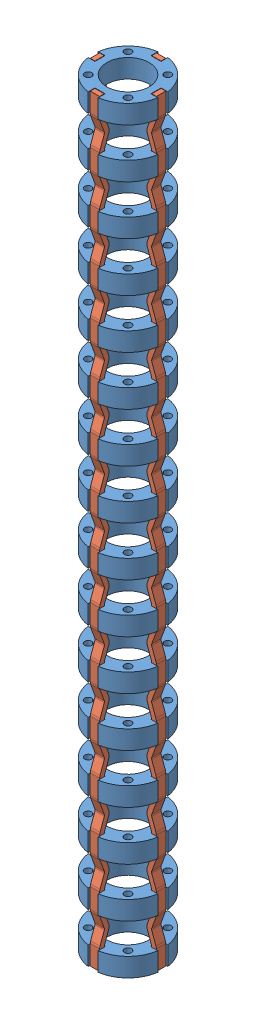
SolidWorks assembly Spine3Segments, configuration Default. Lengths in mm.
Overall size (14.85 161.57 14.85).
20 component instances, 2 part files, 9 mates.
Components (placement in the parent):
- RigidDisc-1: RigidDisc [Default] at (4.4669 6.9477 12.6403) size (14.85 4 14.85)
- RigidDisc-2: RigidDisc [Default] at (4.4669 -3.5523 12.6403) size (14.85 4 14.85)
- RigidDisc-3: RigidDisc [Default] at (4.4669 -14.0523 12.6403) size (14.85 4 14.85)
- RigidDisc-4: RigidDisc [Default] at (4.4669 -24.5523 12.6403) size (14.85 4 14.85)
- RigidDisc-5: RigidDisc [Default] at (4.4669 -35.0523 12.6403) size (14.85 4 14.85)
- Ligament-9: Ligament [Default] at (11.0169 10.9477 11.6403) x (0 -1 0) z (-1 0 0) size (161.57 2 2.03)
- RigidDisc-16: RigidDisc [Default] at (4.4669 -45.5523 12.6403) size (14.85 4 14.85)
- RigidDisc-17: RigidDisc [Default] at (4.4669 -56.0523 12.6403) size (14.85 4 14.85)
- RigidDisc-18: RigidDisc [Default] at (4.4669 -66.5523 12.6403) size (14.85 4 14.85)
- RigidDisc-19: RigidDisc [Default] at (4.4669 -77.0523 12.6403) size (14.85 4 14.85)
- RigidDisc-20: RigidDisc [Default] at (4.4669 -87.5523 12.6403) size (14.85 4 14.85)
- RigidDisc-21: RigidDisc [Default] at (4.4669 -98.0523 12.6403) size (14.85 4 14.85)
- RigidDisc-22: RigidDisc [Default] at (4.4669 -108.5523 12.6403) size (14.85 4 14.85)
- RigidDisc-23: RigidDisc [Default] at (4.4669 -119.0523 12.6403) size (14.85 4 14.85)
- RigidDisc-24: RigidDisc [Default] at (4.4669 -129.5523 12.6403) size (14.85 4 14.85)
- RigidDisc-25: RigidDisc [Default] at (4.4669 -140.0523 12.6403) size (14.85 4 14.85)
- RigidDisc-26: RigidDisc [Default] at (4.4669 -150.5523 12.6403) size (14.85 4 14.85)
- Ligament-11: Ligament [Default] at (3.4669 10.9477 6.0903) x (0 -1 0) z (0 0 1) size (161.57 2 2.03)
- Ligament-12: Ligament [Default] at (-2.0831 10.9477 13.6403) x (0 -1 0) z (1 0 0) size (161.57 2 2.03)
- Ligament-13: Ligament [Default] at (5.4669 10.9477 19.1903) x (0 -1 0) z (0 0 -1) size (161.57 2 2.03)
Mates (geometry in assembly coordinates):
- Coincident21: coincident anti-aligned: plane of RigidDisc-1 through (4.4669 6.9477 13.7153) normal (0 0 -1); plane of Ligament-5 through (-1.0081 -150.626 13.7153) normal (0 0 1)
- Coincident23: coincident anti-aligned: plane of RigidDisc-1 through (-1.5081 6.9477 11.5653) normal (-1 0 0); plane of Ligament-5 through (-1.5081 -188.4786 11.7153) normal (1 0 0)
- Coincident25: coincident anti-aligned: plane of RigidDisc-1 through (3.3919 6.9477 12.6403) normal (1 0 0); plane of Ligament-8 through (3.3919 -150.626 7.1653) normal (-1 0 0)
- Coincident26: coincident anti-aligned: plane of RigidDisc-1 through (5.5419 6.9477 6.6653) normal (0 0 -1); plane of Ligament-8 through (5.3919 -188.4786 6.6653) normal (0 0 1)
- Distance2: distance = 0.075 mm anti-aligned: plane of RigidDisc-1 through (10.4419 6.9477 13.7153) normal (1 0 0); plane of Ligament-9 through (10.5169 -30.9786 13.6403) normal (-1 0 0)
- Distance1: distance = 0.075 mm anti-aligned: plane of RigidDisc-1 through (4.4669 6.9477 11.5653) normal (0 0 1); plane of Ligament-9 through (10.0169 6.874 11.6403) normal (0 0 -1)
- Coincident32: coincident anti-aligned: plane of RigidDisc-1 through (3.3919 6.9477 18.6153) normal (0 0 1); plane of Ligament-10 through (3.5419 -188.4786 18.6153) normal (0 0 -1)
- Coincident33: coincident anti-aligned: plane of RigidDisc-1 through (5.5419 6.9477 12.6403) normal (-1 0 0); plane of Ligament-10 through (5.5419 -150.626 18.1153) normal (1 0 0)
- Coincident34: coincident aligned: plane of RigidDisc-1 through (4.4669 10.9477 12.6403) normal (0 1 0); plane of Ligament-9 through (11.5169 10.9477 13.6403) normal (0 1 0)
